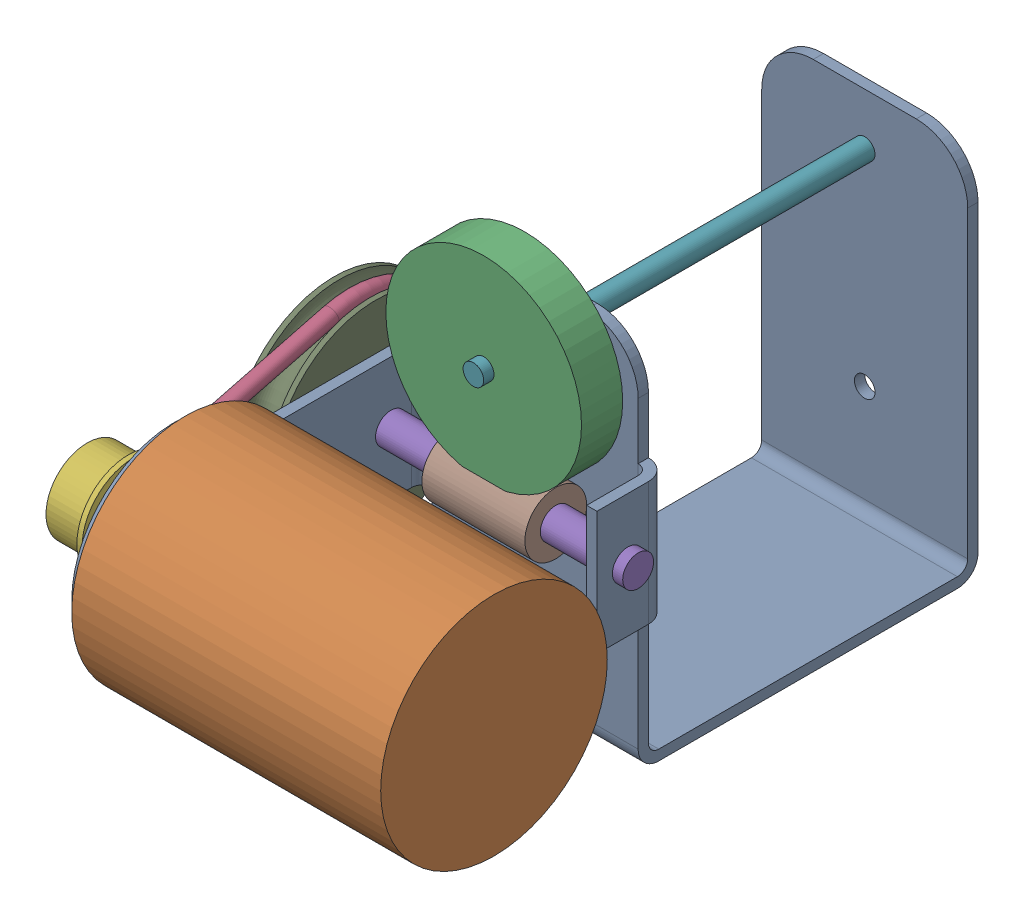
SolidWorks assembly 02_Drive, configuration Default. Lengths in mm.
Overall size (40.22 41 68).
9 component instances, 9 part files, 0 mates.
Components (placement in the parent):
- Bracket.1-1: Bracket.1 [Default] at (-126 0 0) size (24 36.5 66)
- Motor-1: Motor [Default] at origin size (40.22 22 22)
- Gear.1-1: Gear.1 [Default] at (0 0 1) size (19 19 4)
- Band-1: Band [Default] at origin size (1.5 20 35)
- Worm_Axle-1: Worm_Axle [Default] at (10 -2 0) size (30 3 3)
- Wheel_C-1: Wheel_C [Default] at (-0.5 0 0) size (8 10 10)
- Axle.1-1: Axle.1 [Default] at origin size (2 2 40)
- Worm-1: Worm [Default] at (10 -2 0) size (10 6 6)
- Wheel_B-1: Wheel_B [Default] at (-0.5 0 0) size (4 20 20)
